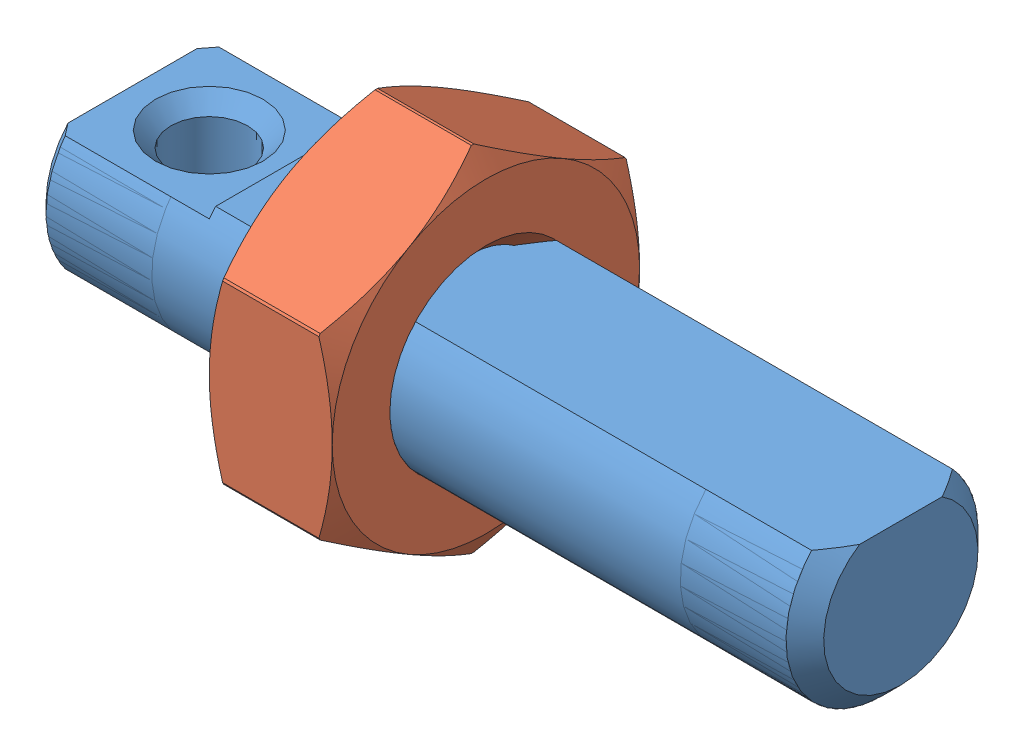
SolidWorks assembly SAIPOZ5_20, configuration Default. Lengths in mm.
Overall size (20 9.2 8).
2 component instances, 2 part files, 0 mates.
Components (placement in the parent):
- SAIPOZ5_20b-1: SAIPOZ5_20b [Milled] at origin size (20 4.2 5)
- KNTR5-1: KNTR5 [Default] at (7.6 0 0) x (-1 0 0) z (0 0 1) size (3.2 9.2 8)
